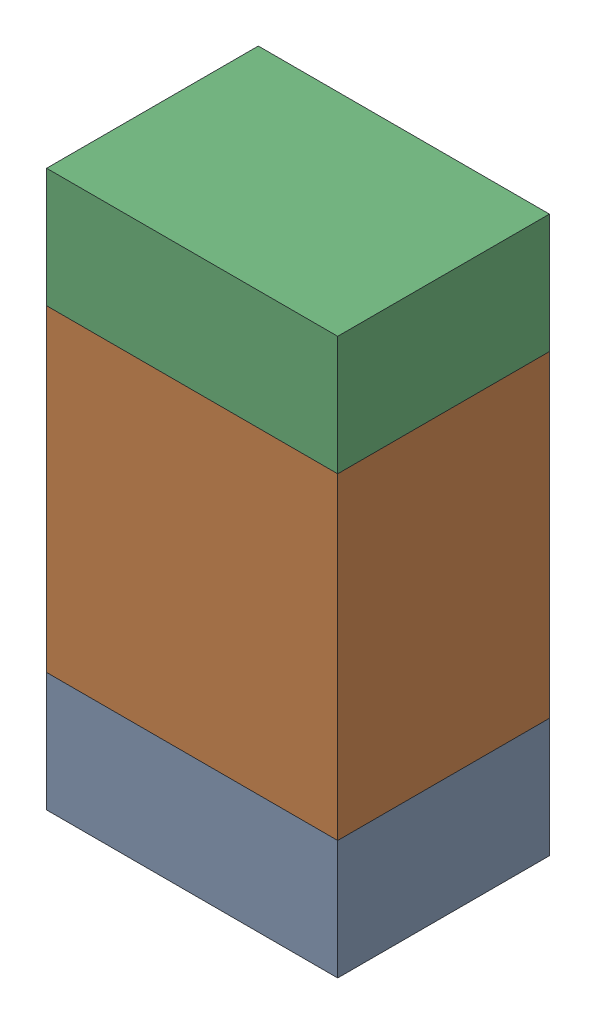
SolidWorks assembly R410PCB, configuration Default. Lengths in mm.
Overall size (0.55 1.05 0.4).
6 component instances, 2 part files, 0 mates.
Components (placement in the parent):
- 846483288-1: 846483288 [Default] at (124.0999 102.3876 0) size (0.55 0.22 0.4)
  - Extruded_12-1: Extruded_12 [Default] at origin size (0.55 0.22 0.4)
- 846483424-1: 846483424 [Default] at (124.0999 102.8001 0) size (0.55 0.6 0.4)
  - Extruded_13-1: Extruded_13 [Default] at origin size (0.55 0.6 0.4)
- 846483288-2: 846483288 [Default] at (124.0999 103.2126 0) size (0.55 0.22 0.4)
  - Extruded_12-1: Extruded_12 [Default] at origin size (0.55 0.22 0.4)
